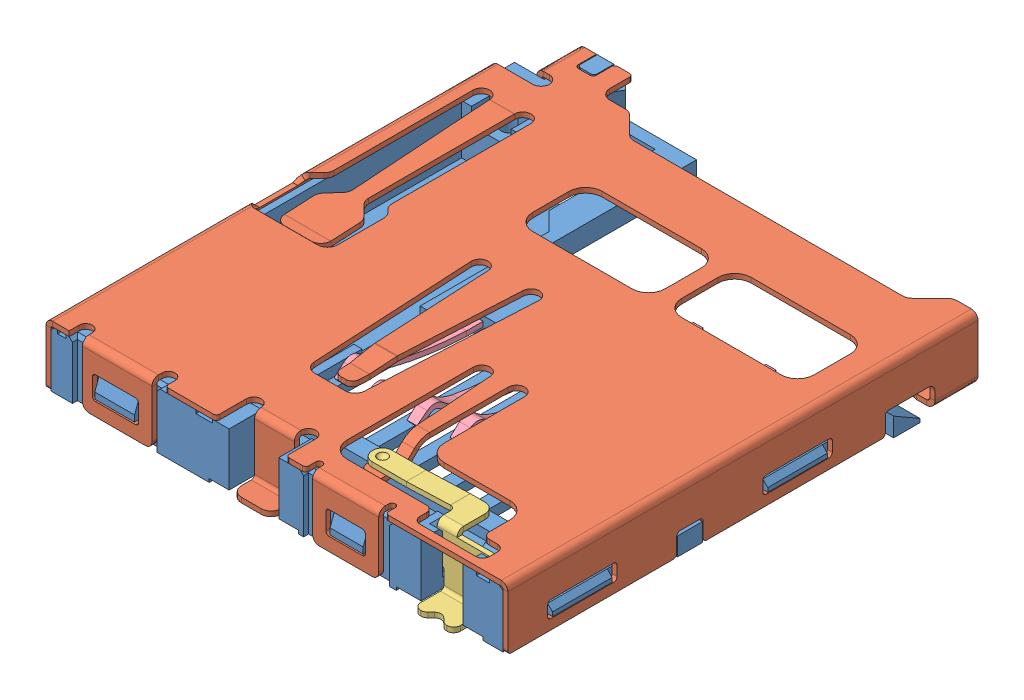
SolidWorks assembly microSD_Connector, configuration Default. Lengths in mm.
Overall size (14.1 2.14 15.45).
12 component instances, 5 part files, 11 mates.
Components (placement in the parent):
- microSD_Body-1: microSD_Body [Default] at origin size (14.1 1.85 15.2)
- microSD_Cover-1: microSD_Cover [Default] at (0 1.7 0) x (1 0 0) z (0 0 -1) size (13.95 1.9 15.2)
- microSD_Card_Detect-1: microSD_Card_Detect [Default] at (4.99 -0.05 7.4) size (4.45 1.9 2.05)
- microSD_Spring-2: microSD_Spring [Default] at (-3.85 1.125 6.9) x (-0.521999 -0.852946 0) z (0.852946 -0.521999 0) size (1.41 10.35 1.43) (hidden)
- microSD_Pin-1: microSD_Pin [11.15] at (5.725 -0.05 -2) x (0 0 1) z (-1 0 0) size (7.35 1.15 0.6)
- microSD_Pin-2: microSD_Pin [11.15] at (4.625 -0.05 -2) x (0 0 1) z (-1 0 0) size (7.35 1.15 0.6)
- microSD_Pin-3: microSD_Pin [11.35] at (3.525 -0.05 -2) x (0 0 1) z (-1 0 0) size (7.35 1.15 0.6)
- microSD_Pin-4: microSD_Pin [11.15] at (2.425 -0.05 -2) x (0 0 1) z (-1 0 0) size (7.35 1.15 0.6)
- microSD_Pin-5: microSD_Pin [11.35] at (1.325 -0.05 -2) x (0 0 1) z (-1 0 0) size (7.35 1.15 0.6)
- microSD_Pin-6: microSD_Pin [11.15] at (0.225 -0.05 -2) x (0 0 1) z (-1 0 0) size (7.35 1.15 0.6)
- microSD_Pin-7: microSD_Pin [10.75] at (-0.875 -0.05 -2) x (0 0 1) z (-1 0 0) size (7.25 1.15 0.6)
- microSD_Pin-8: microSD_Pin [11.15] at (-1.975 -0.05 -2) x (0 0 1) z (-1 0 0) size (7.35 1.15 0.6)
Mates (geometry in assembly coordinates):
- Coincident3: coincident anti-aligned: plane of microSD_Body-1 through (0 1.7 0) normal (0 1 0); plane of microSD_Cover-1 through (0 1.7 0) normal (0 -1 0)
- Coincident9: coincident anti-aligned: plane of microSD_Body-1 through (5.625 -0.001 6.8) normal (0 0 1); plane of microSD_Card_Detect-1 through (4.99 -0.05 6.8) normal (0 0 -1)
- Width5: width anti-aligned: plane of microSD_Body-1 through (4.355 -0.001 6.8) normal (1 0 0); plane of microSD_Card_Detect-1 through (5.625 -0.001 8.8) normal (-1 0 0); plane of microSD_Body-1 through (4.39 0.1 6.95) normal (-1 0 0); plane of microSD_Card_Detect-1 through (5.59 0.1 6.95) normal (1 0 0)
- Width6: width aligned: plane of microSD_Body-1 through (-6.825 1.7 -7.6) normal (-1 0 0); plane of microSD_Cover-1 through (6.825 1.7 -7.6) normal (1 0 0); plane of microSD_Body-1 through (6.825 1.7 0) normal (-1 0 0); plane of microSD_Cover-1 through (-6.825 1.7 0) normal (1 0 0)
- Coincident11: coincident anti-aligned: plane of microSD_Body-1 through (0 0 7.45) normal (0 0 1); plane of microSD_Cover-1 through (0 1.7 7.45) normal (0 0 -1)
- Coincident12: coincident aligned: plane of microSD_Cover-1 through (0 1.85 0) normal (0 1 0); plane of microSD_Card_Detect-1 through (4.99 1.85 7.4) normal (0 1 0)
- Coincident13: coincident aligned: plane of microSD_Body-1 through (-4.725 -0.001 7) normal (0 0 -1); plane of microSD_Spring-2 through (-3.85 1.125 7) normal (0 0 -1)
- Concentric1: concentric: cylinder of microSD_Body-1 through (-3.85 1.125 5.5) axis (0 0 1) radius 0.275; point of microSD_Spring-2
- Coincident14: coincident: point of microSD_Body-1; point of microSD_Pin-1
- Coincident15: coincident: point of microSD_Body-1; point of microSD_Pin-1
- Coincident16: coincident anti-aligned: plane of microSD_Body-1 through (5.425 0.3 -7.601) normal (0 1 0); plane of microSD_Pin-1 through (5.425 0.3 -0.3) normal (0 -1 0)
